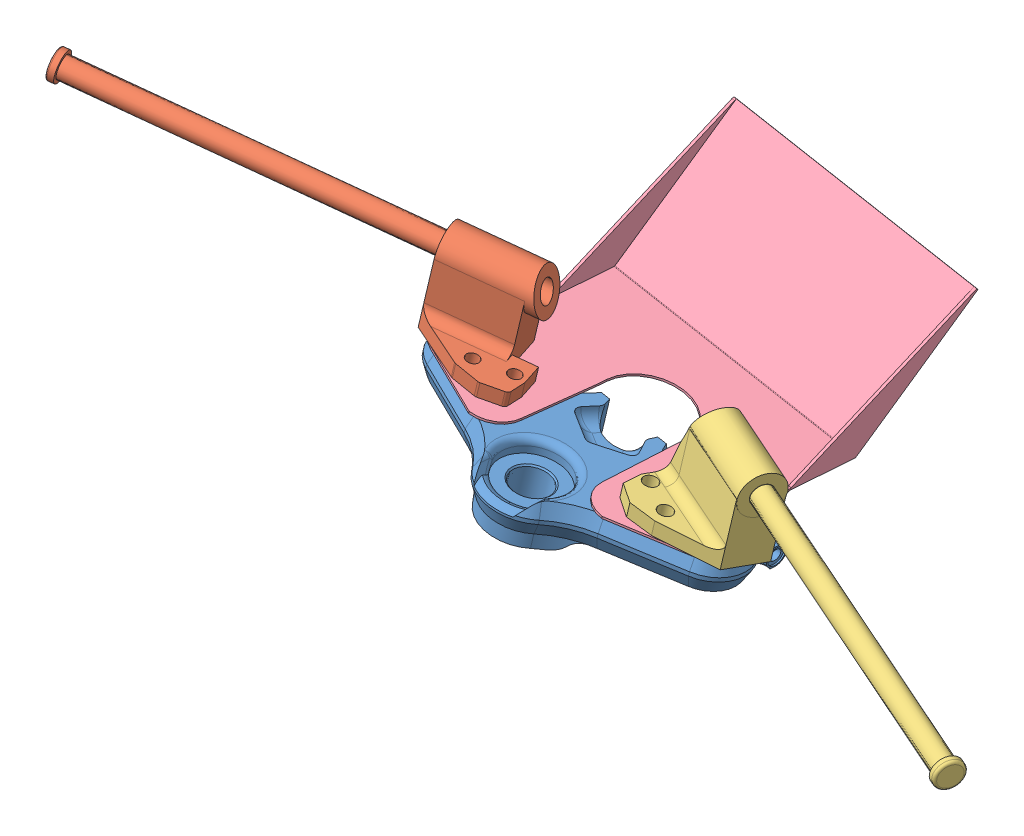
SolidWorks assembly total handle, configuration Default. Lengths in mm.
Overall size (696.4 210.61 316.49).
6 component instances, 4 part files, 8 mates.
Components (placement in the parent):
- base-1: base [Default] at (336.6504 307.5951 624.1205) x (0.984889 -0.173051 0.006897) z (0.006897 0.078988 0.996852) size (232.9 57 110.51)
- Assem4-2: Assem4 [Default] at (242.0059 429.7371 335.6648) x (-0.984898 0.172059 -0.019249) z (-0.005307 0.081126 0.99669) size (308.42 61.89 159.3)
  - handle 2-1: handle 2 [Default] at (0.8695 54.4279 238.7352) x (0.943724 0 0.330735) z (0.330735 0 -0.943724) size (305.14 61.89 61.86)
- assem2-2: assem2 [Default] at (370.0908 12.5504 305.1947) x (0.984889 -0.173051 0.006897) z (0.006897 0.078988 0.996852) size (311.32 63.72 159.81)
  - handle-1: handle [Default] at (-21.0108 332.4031 282.0082) x (0.330735 0 -0.943724) z (0.943724 0 0.330735) size (61.26 63.72 308.42)
- ved dashboard 2 - Copy-1: ved dashboard 2 - Copy [Default] at (337.0528 333.5212 630.7338) x (0.984889 -0.173051 0.006897) z (0.006897 0.078988 0.996852) size (232.9 85.23 223.74)
Mates (geometry in assembly coordinates):
- Coincident6: coincident anti-aligned: cylinder of base-1 through (251.7323 342.2182 577.2238) axis (-0.173051 -0.98174 0.078988) radius 15.5; circle of ved dashboard 2 - Copy-1
- Coincident7: coincident anti-aligned: circle of base-1; circle of ved dashboard 2 - Copy-1
- Concentric13: concentric aligned: cylinder of base-1 through (251.7323 342.2182 577.2238) axis (-0.173051 -0.98174 0.078988) radius 15.5; cylinder of Assem4-2/handle 2-1 through (253.8089 353.9991 576.2759) axis (-0.173051 -0.98174 0.078988) radius 15.5
- Concentric14: concentric aligned: cylinder of base-1 through (428.9137 311.0863 578.4646) axis (-0.173051 -0.98174 0.078988) radius 15.5; cylinder of assem2-2/handle-1 through (430.9903 322.8671 577.5168) axis (-0.173051 -0.98174 0.078988) radius 15.5
- Coincident9: coincident anti-aligned: plane of assem2-2/handle-1 through (389.155 319.2996 568.1225) normal (-0.173051 -0.98174 0.078988); plane of ved dashboard 2 - Copy-1 through (252.0784 344.1817 577.0658) normal (0.173051 0.98174 -0.078988)
- Concentric17: concentric anti-aligned: cylinder of Assem4-2/handle 2-1 through (253.8089 353.9991 576.2759) axis (-0.173051 -0.98174 0.078988) radius 15.5; circle of ved dashboard 2 - Copy-1
- Coincident12: coincident anti-aligned: plane of Assem4-2/handle 2-1 through (222.3494 349.7865 581.5959) normal (-0.173051 -0.98174 0.078988); plane of ved dashboard 2 - Copy-1 through (252.0784 344.1817 577.0658) normal (0.173051 0.98174 -0.078988)
- Concentric20: concentric aligned: cylinder of base-1 through (289.477 336.5269 589.1797) axis (-0.173051 -0.98174 0.078988) radius 4.5; cylinder of Assem4-2/handle 2-1 through (291.5536 348.3077 588.2318) axis (-0.173051 -0.98174 0.078988) radius 4.5
